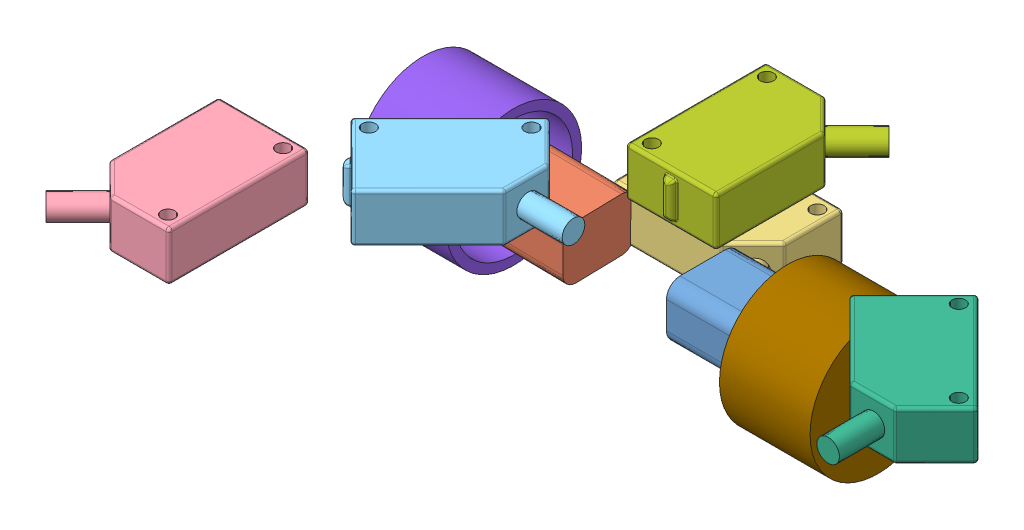
SolidWorks assembly Assem4, configuration Default. Lengths in mm.
Overall size (142.78 67.18 131.05).
9 component instances, 9 part files, 0 mates.
Components (placement in the parent):
- 16mm motor-1: 16mm motor [Default] at (15.7373 8.2842 32.1166) size (40 12 16)
- 16mm motor 2-1: 16mm motor 2 [Default] at (-36.7647 20.0814 32.5908) x (-0.999775 0.020421 0.005745) z (0.005393 -0.017264 0.999836) size (40 12 16)
- omron-1: omron [Default] at (-10.441 8.5434 15.3279) size (37.72 10.8 25.16)
- omron2-1: omron2 [Default] at (-28.3518 55.6226 115.3553) x (0 0 1) z (-1 0 0) size (37.72 10.8 25.16)
- omron3-1: omron3 [Default] at (-16.5708 40.9516 70.5537) x (0.707107 0 -0.707107) z (0.707107 0 0.707107) size (37.72 10.8 25.16)
- omron4-1: omron4 [Default] at (58.8023 27.4022 43.5456) x (0.707107 0 0.707107) z (-0.707107 0 0.707107) size (37.72 10.8 25.16)
- omron5-1: omron5 [Default] at (20.0003 50.2106 42.9115) x (0 0 -1) z (1 0 0) size (37.72 10.8 25.16)
- tekerlek-1: tekerlek [Default] at (-40.6213 14.2791 32.4879) x (-1 0 0) z (0 0 -1) size (20 30 30)
- tekerlek2-1: tekerlek2 [Default] at (19.3742 14.2401 32.047) size (20 30 30)
